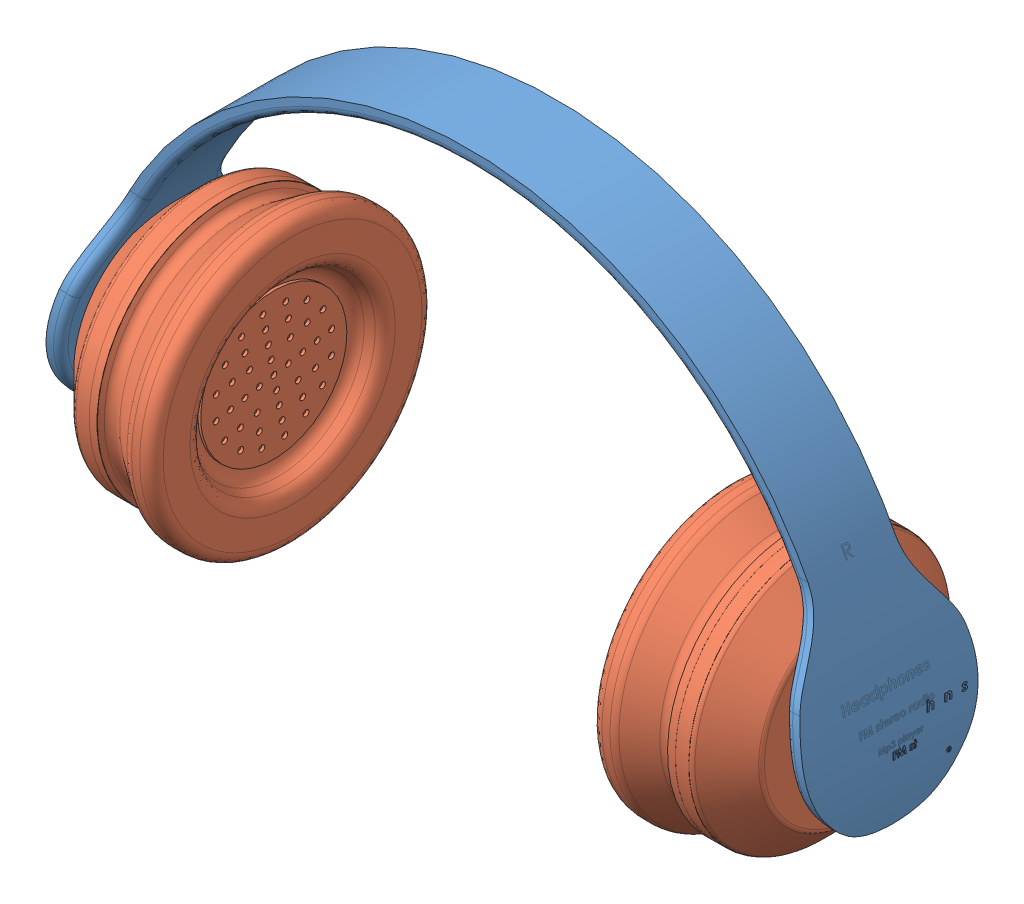
SolidWorks assembly Assem1, configuration Default. Lengths in mm.
Overall size (261.33 171.79 114.63).
3 component instances, 2 part files, 6 mates.
Components (placement in the parent):
- Headphone-TOP-1: Headphone-TOP [Default] at (17.1907 52.0546 312.7275) size (270.76 144.49 65.4)
- Earphone-2: Earphone [Default] at (143.1907 67.5803 342.7275) x (0 -0.975923 0.218113) z (0 -0.218113 -0.975923) size (96 51.41 96)
- Earphone-3: Earphone [Default] at (-108.8093 67.5803 342.7275) x (0 -0.98247 -0.186421) z (0 -0.186421 0.98247) size (96 51.41 96)
Mates (geometry in assembly coordinates):
- Coincident1: coincident: line of Headphone-TOP-1 through (135.1459 67.5803 342.7275) axis (1 0 0); line of Earphone-2 through (117.721 67.5803 342.7275) axis (1 0 0)
- Tangent1: tangent: cylinder of Headphone-TOP-1 through (17.1907 52.0546 375.3308) axis (0 0 -1) radius 126; plane of Earphone-2 through (143.1907 82.2191 339.4558) normal (1 0 0)
- Lock1: lock: unknown of Headphone-TOP-1; unknown of Earphone-2
- Coincident2: coincident: line of Headphone-TOP-1 through (-108.8093 67.5803 342.7275) axis (1 0 0); axis of Earphone-3 through (-81.0828 67.5803 342.7275) axis (-1 0 0)
- Tangent2: tangent: cylinder of Headphone-TOP-1 through (17.1907 52.0546 375.3308) axis (0 0 -1) radius 126; plane of Earphone-3 through (-108.8093 82.3173 345.5238) normal (-1 0 0)
- Lock2: lock: unknown of Headphone-TOP-1; unknown of Earphone-3
